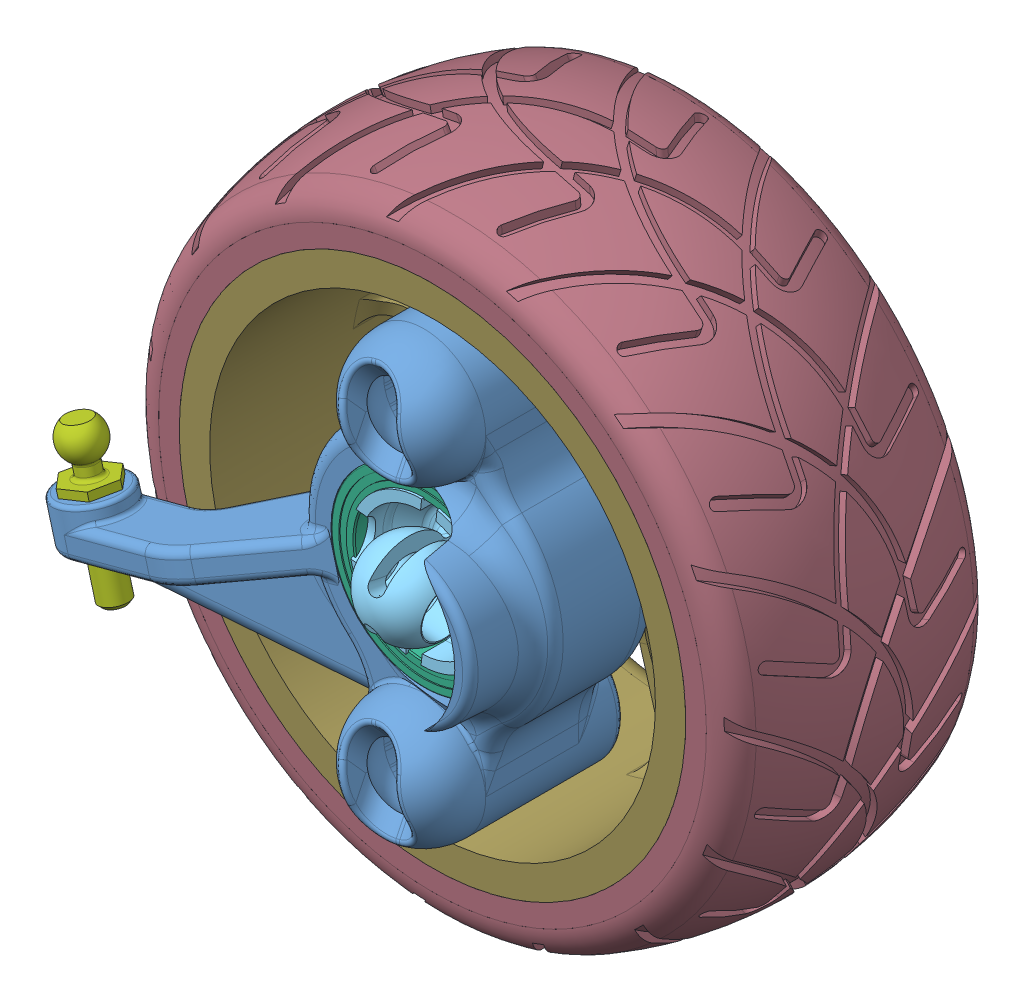
SolidWorks assembly Front hub carrier L assem, configuration Default. Lengths in mm.
Overall size (73 73 35.12).
17 component instances, 13 part files, 23 mates.
Components (placement in the parent):
- Front hub carrier L-1: Front hub carrier L [Default] at origin size (46.22 44.77 21.73)
- Pillow Ball Bushing-1: Pillow Ball Bushing [Default] at (0 16.0337 7.1437) x (1 0 0) z (0 1 0) size (8.26 2.64 8.26)
- Pillow Ball Retainer-1: Pillow Ball Retainer [Default] at (0 16.0337 2.3813) x (-0.973225 0.229855 0) z (0 0 -1) size (9.02 9.02 5.71)
- Pillow Ball Bushing-4: Pillow Ball Bushing [Default] at (0 -16.0337 7.1437) x (1 0 0) z (0 1 0) size (8.26 2.64 8.26)
- Pillow Ball Retainer-2: Pillow Ball Retainer [Default] at (0 -16.0337 2.3813) x (-0.973225 0.229855 0) z (0 0 -1) size (9.02 9.02 5.71)
- Rear Hub Bearing-1: Rear Hub Bearing [Default] at (0 0 -3.9688) size (12.7 12.7 3.17)
- front axle-1: front axle [Default] at (0 0 2.0002) x (-0.993741 0.11171 0) z (0 0 1) size (14.29 14.71 32.13)
- front hub bearing-1: front hub bearing [Default] at (0 0 5.5563) x (1 0 0) z (0 1 0) size (19.05 3.17 19.05)
- 0.1875 Ball stud 0.375-1: 0.1875 Ball stud 0.375 [Default] at (-30.2632 -4.822 10.9537) x (-0.651089 -0.174459 -0.73868) z (-0.258819 0.965926 0) size (5.5 4.76 15.1)
- Rear hex hub assem-1: Rear hex hub assem [Default] at (0 0 -8.0962) x (-0.91646 -0.400127 0) z (0 0 1) size (13.93 12.36 5.46)
  - Hex Drive-1: Hex Drive [Default] at origin size (13.93 12.06 5.46)
  - Hex axle pin-1: Hex axle pin [Default] x (-0.276481 0.159627 -0.94767) z (0.5 0.866025 0) size (2.38 2.38 9.53)
  - Hex retaining O-Ring-1: Hex retaining O-Ring [Default] x (1 0 0) z (0 1 0) size (12.36 1.59 12.36)
- ANSI B18.2.4.4M - M5 x 0-1: ANSI B18.2.4.4M - M5 x 0 [Default] at (0 0 -13.5572) x (0 0 -1) z (0.994729 -0.102542 0) size (5 11.8 11.8)
- Wheel  assem-1: Wheel  assem [Default] at (0 0 6.2547) x (0.11171 0.993741 0) z (-0.993741 0.11171 0) size (66.04 26.78 66.04)
  - Wheel-1: Wheel [Default] at origin size (51.94 26.78 51.94)
  - Tire-1: Tire [Default] at (0 13.2715 0) x (0 1 0) z (0 0 1) size (26.54 66.04 66.04)
Mates (geometry in assembly coordinates):
- Concentric1: concentric anti-aligned: cylinder of Front hub carrier L-1 through (0 16.0337 7.1437) axis (0 0 -1) radius 6.35; cylinder of Pillow Ball Retainer-1 through (0 16.0337 -2.6987) axis (0 0 1) radius 4.5085
- Coincident1: coincident anti-aligned: plane of Pillow Ball Bushing-1 through (0 16.0337 2.3813) normal (0 0 -1); plane of Pillow Ball Retainer-1 through (0 16.0337 2.3813) normal (0 0 1)
- Concentric2: concentric anti-aligned: cylinder of Pillow Ball Bushing-1 through (0 16.0337 5.0167) axis (0 0 -1) radius 2.0638; cylinder of Pillow Ball Retainer-1 through (0 16.0337 -2.6987) axis (0 0 1) radius 4.5085
- Concentric3: concentric: sphere of Front hub carrier L-1; sphere of Pillow Ball Bushing-1
- Concentric4: concentric aligned: cylinder of Pillow Ball Bushing-4 through (0 -16.0337 52.6062) axis (0 0 1) radius 4.1275; cylinder of Pillow Ball Retainer-2 through (0 -16.0337 -2.6987) axis (0 0 1) radius 4.5085
- Coincident2: coincident anti-aligned: plane of Pillow Ball Bushing-4 through (0 -16.0337 2.3813) normal (0 0 -1); plane of Pillow Ball Retainer-2 through (0 -16.0337 2.3813) normal (0 0 1)
- Concentric5: concentric anti-aligned: cylinder of Front hub carrier L-1 through (0 -16.0337 7.1437) axis (0 0 -1) radius 6.35; cylinder of Pillow Ball Retainer-2 through (0 -16.0337 -2.6987) axis (0 0 1) radius 4.5085
- Concentric6: concentric: sphere of Front hub carrier L-1; sphere of Pillow Ball Bushing-4
- Concentric7: concentric aligned: cylinder of Front hub carrier L-1 through (0 0 -2.3813) axis (0 0 -1) radius 6.35; cylinder of Rear Hub Bearing-1 through (0 0 -2.3813) axis (0 0 -1) radius 6.35
- Coincident3: coincident anti-aligned: plane of Front hub carrier L-1 through (0 0 -2.3813) normal (0 0 -1); plane of Rear Hub Bearing-1 through (0 0 -2.3813) normal (0 0 1)
- Concentric8: concentric anti-aligned: cylinder of Front hub carrier L-1 through (0 0 12.8767) axis (0 0 -1) radius 6.0325; cylinder of front axle-1 through (0 0 -19.3357) axis (0 0 1) radius 2.3813
- Concentric9: concentric anti-aligned: cylinder of Front hub carrier L-1 through (0 0 12.8767) axis (0 0 -1) radius 6.0325; cylinder of front hub bearing-1 through (0 0 3.9688) axis (0 0 1) radius 7.1437
- Coincident4: coincident anti-aligned: plane of Front hub carrier L-1 through (0 0 3.9688) normal (0 0 1); plane of front hub bearing-1 through (0 0 3.9688) normal (0 0 -1)
- Coincident5: coincident aligned: plane of front axle-1 through (0 0 7.1437) normal (0 0 -1); circle of front hub bearing-1
- Concentric10: concentric aligned: cylinder of Front hub carrier L-1 through (-30.2632 -4.822 10.9537) axis (-0.258819 0.965926 0) radius 1.1303; cylinder of 0.1875 Ball stud 0.375-1 through (-27.7979 -14.0224 10.9537) axis (-0.258819 0.965926 0) radius 1.4224
- Coincident6: coincident anti-aligned: plane of Front hub carrier L-1 through (-30.2632 -4.822 10.9537) normal (-0.258819 0.965926 0); plane of 0.1875 Ball stud 0.375-1 through (-30.2632 -4.822 10.9537) normal (0.258819 -0.965926 0)
- Coincident8: coincident anti-aligned: circle of Rear Hub Bearing-1; plane of Rear hex hub assem-1/Hex Drive-1 through (0 0 -5.5563) normal (0 0 1)
- Parallel2: parallel anti-aligned: cylinder of front axle-1 through (0.8216 7.309 -7.9566) axis (-0.11171 -0.993741 0) radius 1.1938; cylinder of Rear hex hub assem-1/Hex axle pin-1 through (-0.532 -4.7327 -8.0962) axis (0.11171 0.993741 0) radius 1.1906
- Concentric15: concentric anti-aligned: cylinder of front axle-1 through (0 0 -19.3357) axis (0 0 1) radius 2.3813; cylinder of Rear hex hub assem-1/Hex Drive-1 through (0 0 -5.1753) axis (0 0 -1) radius 2.3813
- Concentric17: concentric aligned: cylinder of front axle-1 through (0 0 -19.3357) axis (0 0 1) radius 2.3813; cylinder of ANSI B18.2.4.4M - M5 x 0-1 through (0 0 -18.1242) axis (0 0 1) radius 2.067
- Concentric18: concentric anti-aligned: cylinder of front axle-1 through (0 0 -19.3357) axis (0 0 1) radius 2.3813; cylinder of Wheel  assem-1/Wheel-1 through (0 0 6.2547) axis (0 0 -1) radius 2.3813
- Coincident9: coincident anti-aligned: plane of Rear hex hub assem-1/Hex Drive-1 through (-0.7781 -6.9221 -5.5563) normal (0.400127 -0.91646 0); plane of Wheel  assem-1/Wheel-1 through (-0.7781 -6.9221 -10.6363) normal (-0.400127 0.91646 0)
- Coincident10: coincident anti-aligned: plane of Rear hex hub assem-1/Hex Drive-1 through (0 0 -10.6363) normal (0 0 -1); plane of Wheel  assem-1/Wheel-1 through (0 0 -10.6363) normal (0 0 1)
